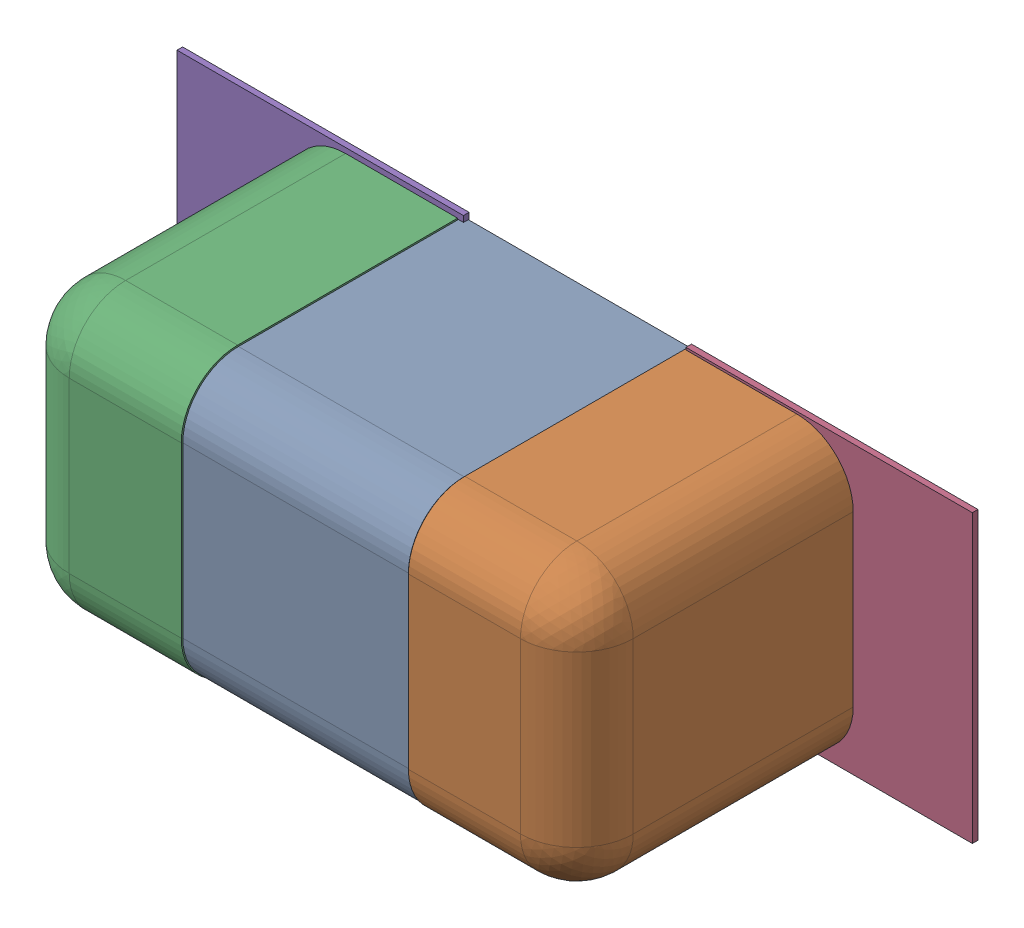
SolidWorks assembly C23, configuration Défaut. Lengths in mm.
Overall size (1.41 0.51 0.5).
8 component instances, 4 part files, 0 mates.
Components (placement in the parent):
- 6324936672-1: 6324936672 [Défaut] at (51.9938 -10.9348 0) x (-1 0 0) z (0 1 0) size (1 0.5 0.5)
  - Open CASCADE STEP translator 7.5 2.131.1.1-1: Open CASCADE STEP translator 7.5 2.131.1.1 [Défaut] at origin size (0.4 0.5 0.5)
  - Open CASCADE STEP translator 7.5 2.131.1.2-1: Open CASCADE STEP translator 7.5 2.131.1.2 [Défaut] at origin size (0.3 0.5 0.5)
  - Open CASCADE STEP translator 7.5 2.131.1.3-1: Open CASCADE STEP translator 7.5 2.131.1.3 [Défaut] at origin size (0.3 0.5 0.5)
- 6504207776-1: 6504207776 [Défaut] at (52.4511 -10.9348 0) size (0.51 0.51 0.01)
  - Extruded-1: Extruded [Défaut] at origin size (0.51 0.51 0.01)
- 6504207776-2: 6504207776 [Défaut] at (51.5488 -10.9296 0) size (0.51 0.51 0.01)
  - Extruded-1: Extruded [Défaut] at origin size (0.51 0.51 0.01)
